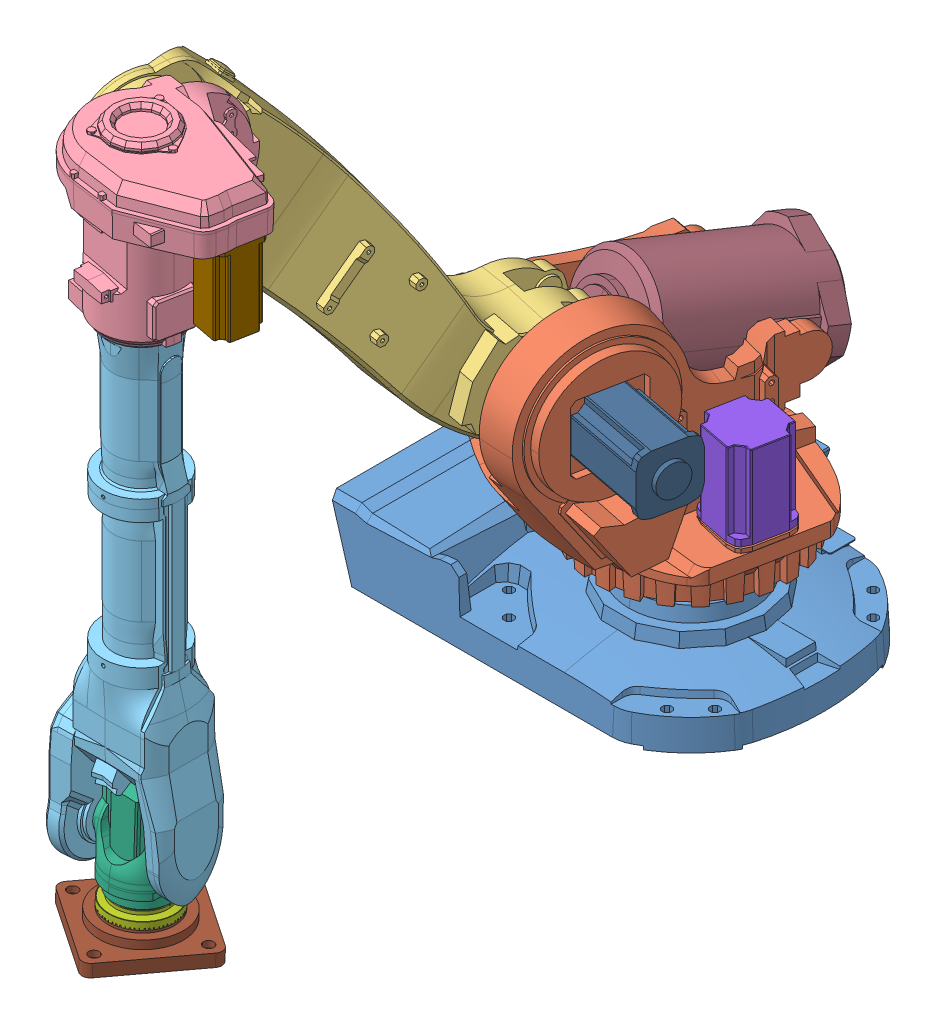
SolidWorks assembly Assablage robot, configuration MEP. Lengths in mm.
Overall size (571.56 1219.67 1120.63).
16 component instances, 14 part files, 35 mates.
Components (placement in the parent):
- BASE-1: BASE [Default] at (395.3055 -156.1762 -1.421) x (1 0 0) z (0 1 0)
- SUPPORT  BASE-1: SUPPORT  BASE [Default] at (335.9973 -366.0232 -56.0681) x (-0.189939 0 0.981796) z (0 1 0)
- BRAS PRINCIPAL-1: BRAS PRINCIPAL [Default] at (579.7547 -213.9219 -807.6382) x (-0.130606 -0.726068 0.675105) z (-0.137909 0.687622 0.712851)
- MOTEUR SECONDAIRE-2: MOTEUR SECONDAIRE [Default] at (608.053 1015.326 -1473.2398) x (0 -1 0) z (-0.189939 0 0.981796) size (263.13 310.72 291.77)
- BRAS SECONDAIRE-1: BRAS SECONDAIRE [Default] at (175.6725 1563.5556 -1546.1916) x (0 -1 0) z (0 0 1)
- SUPPORT PINCE-1: SUPPORT PINCE [Default] at (176.5697 1931.3024 2897.3419) x (0 -0.999428 0.033831) z (0 -0.033831 -0.999428)
- ATTACHE PINCE-1: ATTACHE PINCE [Default] at (-1859.1644 1962.048 1612.9264) x (0 -0.999428 0.033831) z (0.902256 -0.014588 -0.430954)
- MOTEUR SECONDAIRE #2-1: MOTEUR SECONDAIRE #2 [Default] at (2493.7415 161.7326 93.9145) x (-0.189939 0 0.981796) z (-0.981796 0 -0.189939)
- MOTEUR SECONDAIRE #3-1: MOTEUR SECONDAIRE #3 [Default] at (472.8165 1041.6843 -1499.2563) x (0 -1 0) z (-0.189939 0 0.981796)
- MOTEUR SECONDAIRE #5-1: MOTEUR SECONDAIRE #5 [Default] at (962.7151 62.25 286.6211) x (-0.189939 0 0.981796) z (-0.981796 0 -0.189939)
- ADAPTATEUR-1: ADAPTATEUR [Défaut] at (175.4272 -188.8301 712.8173) x (0.565776 -0.027895 -0.824087) z (0.824559 0.019141 0.565452)
- STD-ROBOT2019-SUPPORT OUTILS-1: STD-ROBOT2019-SUPPORT OUTILS [91274A308] at (172.4669 -160.0405 749.8493) x (-0.755331 0.022171 0.654968) z (0 0.999428 -0.033831) size (14.29 14.29 35.96)
- STD-ROBOT2019-SUPPORT OUTILS-6: STD-ROBOT2019-SUPPORT OUTILS [91274A308] at (144.0115 -162.0549 690.3425) x (-0.189878 -0.033215 -0.981246) z (0 0.999428 -0.033831) size (14.29 14.29 35.96)
- STD-ROBOT2019-SUPPORT OUTILS-7: STD-ROBOT2019-SUPPORT OUTILS [91274A308] at (209.8031 -161.8814 695.4669) x (0.945209 0.011045 0.326278) z (0 0.999428 -0.033831) size (14.29 14.29 35.96)
- PISTON-1: PISTON [Default] at (384.4192 -426.2776 149.1004) x (-0.189514 0.066836 0.979601) z (0.012695 0.997764 -0.06562)
- TIGE PISTON-1: TIGE PISTON [Default] at (439.8462 -416.1012 131.1425) x (-0.174372 0.067386 0.982371) z (-0.058585 0.995178 -0.078663)
Mates (geometry in assembly coordinates):
- Coïncidente2: coincident aligned: plane of BASE-1 through (306.882 0 -3.2236) normal (0 1 0); plane of assembly through (0 0 0) normal (0 1 0)
- Coïncidente3: coincident anti-aligned: plane of BASE-1 through (0 -380.3348 -181.2236) normal (-1 0 0); plane of assembly through (0 0 0) normal (1 0 0)
- Coaxiale2: concentric aligned: circle of BASE-1; circle of SUPPORT  BASE-1
- Coïncidente16: coincident anti-aligned: plane of BASE-1 through (306.882 0 -3.2236) normal (0 1 0); plane of SUPPORT  BASE-1 through (306.882 0 -3.2236) normal (0 -1 0)
- Coaxiale4: concentric aligned: circle of SUPPORT  BASE-1; circle of BRAS PRINCIPAL-1
- Coïncidente17: coincident anti-aligned: plane of SUPPORT  BASE-1 through (342.4889 116 -266.2486) normal (-0.981796 0 -0.189939); plane of BRAS PRINCIPAL-1 through (261.7648 283.25 151.0147) normal (0.981796 0 0.189939)
- Coaxiale5: concentric anti-aligned: circle of BRAS PRINCIPAL-1; circle of MOTEUR SECONDAIRE-2
- Coïncidente29: coincident anti-aligned: plane of BRAS PRINCIPAL-1 through (53.2333 723.3284 583.9718) normal (0.981796 0 0.189939); plane of MOTEUR SECONDAIRE-2 through (40.9822 723.3284 647.2977) normal (-0.981796 0 -0.189939)
- Parallèle9: parallel aligned: plane of MOTEUR SECONDAIRE-2 through (172.4272 860.3284 708.8853) normal (0 1 0)
- Coaxiale6: concentric aligned: circle of MOTEUR SECONDAIRE-2; circle of BRAS SECONDAIRE-1
- Coïncidente31: coincident anti-aligned: plane of MOTEUR SECONDAIRE-2 through (271.5193 608.0957 822.4721) normal (0 -1 0); plane of BRAS SECONDAIRE-1 through (232.1772 608.0957 612.6045) normal (0 1 0)
- Parallèle10: parallel aligned: plane of BRAS SECONDAIRE-1 through (175.6725 1563.5556 -1546.1916) normal (0 0 1)
- Coaxiale7: concentric anti-aligned: circle of SUPPORT PINCE-1; circle of ATTACHE PINCE-1
- Coïncidente37: coincident anti-aligned: plane of SUPPORT PINCE-1 through (175.4272 -155.5949 668.2174) normal (0 -0.999428 0.033831); plane of ATTACHE PINCE-1 through (211.5174 -154.7085 694.4044) normal (0 0.999428 -0.033831)
- Coaxiale9: concentric anti-aligned: circle of SUPPORT  BASE-1; circle of MOTEUR SECONDAIRE #2-1
- Coïncidente45: coincident anti-aligned: plane of SUPPORT  BASE-1 through (415.3704 108.75 17.7647) normal (0 1 0); plane of MOTEUR SECONDAIRE #2-1 through (415.3704 108.75 17.7647) normal (0 -1 0)
- Parallèle17: parallel aligned: plane of SUPPORT  BASE-1 through (464.2 35.9995 2.2824) normal (0.981796 0 0.189939); plane of MOTEUR SECONDAIRE #2-1 through (459.5513 243.25 26.3119) normal (0.981796 0 0.189939)
- Coaxiale10: concentric aligned: circle of SUPPORT  BASE-1; circle of MOTEUR SECONDAIRE #5-1
- Parallèle18: parallel anti-aligned: plane of SUPPORT  BASE-1 through (335.6194 335.75 211.137) normal (0 -1 0); plane of MOTEUR SECONDAIRE #5-1 through (344.1667 328.25 166.9562) normal (0 1 0)
- Coïncidente49: coincident anti-aligned: plane of SUPPORT  BASE-1 through (334.1949 335.75 218.5005) normal (0.981796 0 0.189939); plane of MOTEUR SECONDAIRE #5-1 through (344.1667 283.25 166.9562) normal (-0.981796 0 -0.189939)
- Coaxiale11: concentric anti-aligned: circle of MOTEUR SECONDAIRE-2; circle of MOTEUR SECONDAIRE #3-1
- Parallèle19: parallel aligned: plane of MOTEUR SECONDAIRE-2 through (327.3093 860.3289 734.8322) normal (0.981796 0 0.189939); plane of MOTEUR SECONDAIRE #3-1 through (332.2585 778.3284 709.2501) normal (0.981796 0 0.189939)
- Coïncidente52: coincident anti-aligned: plane of MOTEUR SECONDAIRE-2 through (300.3501 790.8284 703.0771) normal (0 -1 0); plane of MOTEUR SECONDAIRE #3-1 through (300.3501 790.8284 703.0771) normal (0 1 0)
- Coaxiale12: concentric aligned: circle of ATTACHE PINCE-1; circle of ADAPTATEUR-1
- Coïncidente53: coincident anti-aligned: plane of ATTACHE PINCE-1 through (175.4272 -166.6178 712.0654) normal (0 -0.999428 0.033831); plane of ADAPTATEUR-1 through (161.2828 -165.9204 732.6676) normal (0 0.999428 -0.033831)
- AngleLimite1: limit planar angle = 0.1911 rad aligned: plane of BASE-1 through (395.3055 -156.1762 -1.421) normal (1 0 0); plane of SUPPORT  BASE-1 through (317.7869 -366.0232 -59.5911) normal (0.981796 0 0.189939)
- Coaxiale15: concentric aligned: circle of BRAS SECONDAIRE-1; circle of SUPPORT PINCE-1
- Largeur5: width aligned: plane of BRAS SECONDAIRE-1 through (223.9272 -172.6716 771.3853) normal (-1 0 0); plane of SUPPORT PINCE-1 through (125.9272 -72.6716 708.8853) normal (1 0 0); plane of BRAS SECONDAIRE-1 through (126.9272 -72.6716 708.8853) normal (-1 0 0); plane of SUPPORT PINCE-1 through (222.9272 -72.6716 708.8853) normal (1 0 0)
- AngleLimite5: limit planar angle = 0.033837 rad aligned: line of BRAS SECONDAIRE-1 through (175.6725 1111.4413 708.8084) axis (0 1 0); line of SUPPORT PINCE-1 through (176.5697 86.8411 703.4857) axis (0 0.999428 -0.033831)
- Coaxiale16: concentric aligned: cylinder of ATTACHE PINCE-1 through (172.4669 -171.3293 750.2315) axis (0 -0.999428 0.033831) radius 3.9688; cylinder of ADAPTATEUR-1 through (172.4669 -179.6121 750.5118) axis (0 -0.999428 0.033831) radius 7.9375
- Coaxiale17: concentric anti-aligned: cylinder of ADAPTATEUR-1 through (172.4669 -179.6121 750.5118) axis (0 -0.999428 0.033831) radius 7.9375; cylinder of STD-ROBOT2019-SUPPORT OUTILS-1 through (172.4669 -194.9456 751.0309) axis (0 0.999428 -0.033831) radius 7.1437
- Coïncidente74: coincident aligned: cone of ATTACHE PINCE-1 through (172.4669 -160.3356 749.8593) axis (0 0.999428 -0.033831); circle of STD-ROBOT2019-SUPPORT OUTILS-1
- Coaxiale19: concentric aligned: circle of SUPPORT  BASE-1; circle of PISTON-1
- Largeur6: width aligned: plane of SUPPORT  BASE-1 through (321.9119 218.7974 -146.1973) normal (-0.981796 0 -0.189939); plane of PISTON-1 through (163.3111 116 -300.9124) normal (0.981796 0 0.189939); plane of SUPPORT  BASE-1 through (144.9264 215.4662 -192.4563) normal (-0.981796 0 -0.189939); plane of PISTON-1 through (321.6497 215.4662 -158.2672) normal (0.981796 0 0.189939)
- Coaxiale20: concentric anti-aligned: circle of PISTON-1; circle of TIGE PISTON-1
